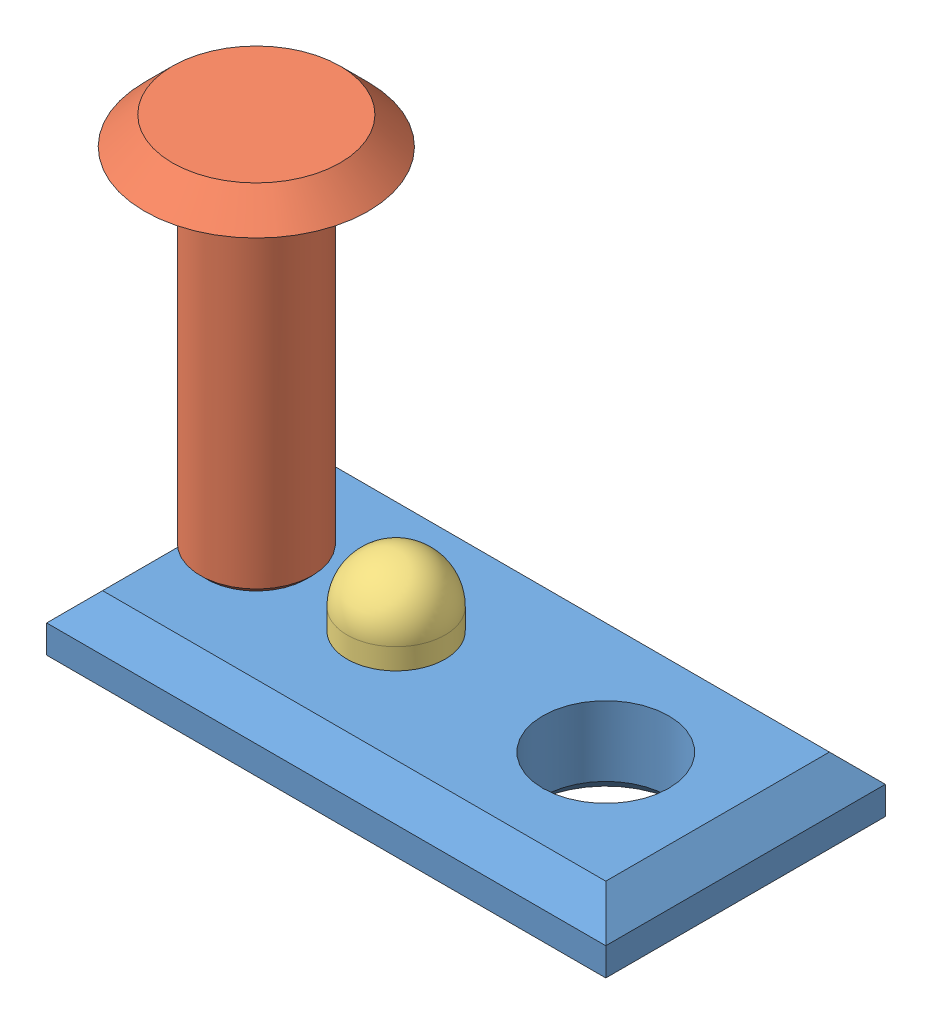
SolidWorks assembly E56, configuration Predeterminado. Lengths in mm.
Overall size (215.25 165 100).
3 component instances, 3 part files, 5 mates.
Components (placement in the parent):
- P56.3-1: P56.3 [Predeterminado] at origin size (200 30 100)
- P56.1-1: P56.1 [Predeterminado] at (-75 -5 0) x (0 1 0) z (0.006158 0 -0.999981) size (160 80 80)
- P56.2-2: P56.2 [Predeterminado] at (-25 -5 0) x (0 1 0) z (0.03705 0 0.999313) size (50 35 35)
Mates (geometry in assembly coordinates):
- Coincidente1: coordinate: point of P56.3-1
- Concéntrica3: concentric: cylinder of P56.3-1 through (-25 -10 0) axis (0 1 0) radius 15; cylinder of P56.2-2 through (-25 -5 0) axis (0 -1 0) radius 15
- Coincidente2: coincident aligned: circle of P56.3-1; circle of P56.2-2
- Concéntrica4: concentric: cylinder of P56.3-1 through (-75 -10 0) axis (0 1 0) radius 7.5; cylinder of P56.1-1 through (-75 155 0) axis (0 1 0) radius 7.5
- Coincidente3: coincident anti-aligned: circle of P56.3-1; circle of P56.1-1
